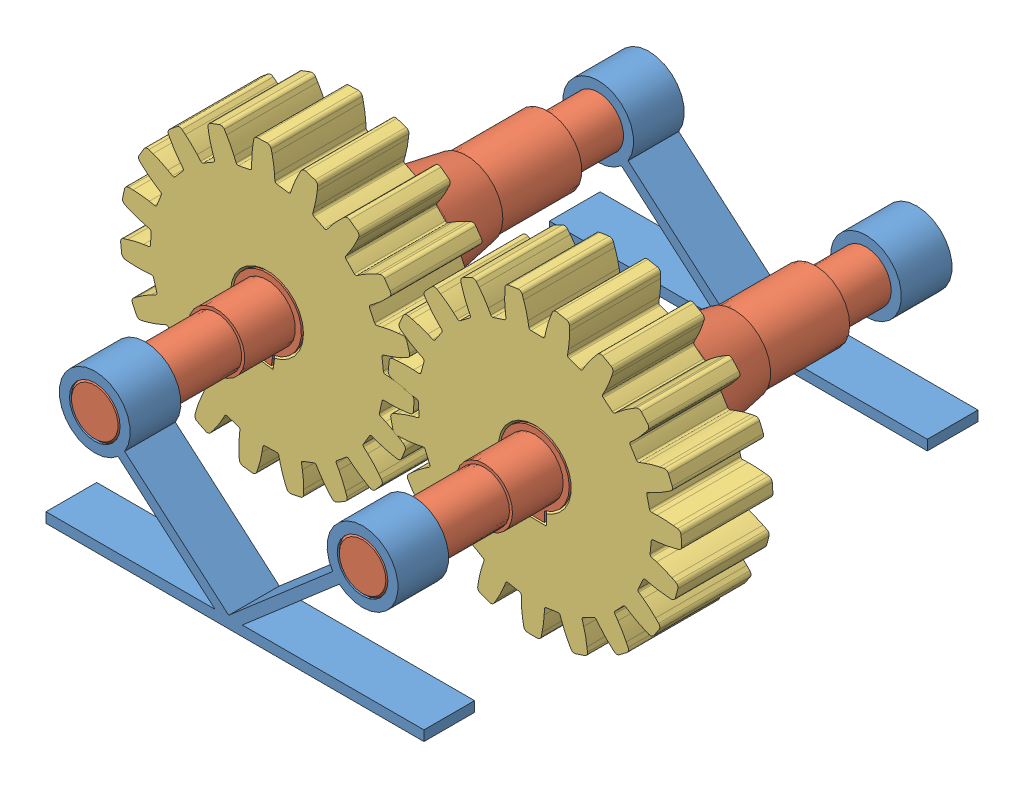
SolidWorks assembly Gear-Box-Assembly, configuration Default. Lengths in mm.
Overall size (287.15 162.37 273.36).
6 component instances, 3 part files, 16 mates.
Components (placement in the parent):
- Base-1: Base [Default] at (37.7602 101.1574 169.9785) size (186.47 77.1 25)
- Shaft-1: Shaft [Default] at (103.8202 101.1574 45.8002) x (0 0 1) z (0.999858 -0.016835 0) size (273.36 46 46)
- Shaft-2: Shaft [Default] at (-28.2998 101.1574 45.8002) x (0 0 1) z (0.991113 -0.133025 0) size (273.36 46 46)
- Spur-Gear-1: Spur-Gear [Default] at (103.8202 101.1574 74.9785) x (-0.999858 0.016835 0) z (0 0 1) size (144.83 144.39 45)
- Spur-Gear-2: Spur-Gear [Default] at (-28.2998 101.1574 74.9785) x (-0.991113 0.133025 0) z (0 0 1) size (144.83 144.39 45)
- Base-2: Base [Default] at (37.7602 101.1574 -78.378) size (186.47 77.1 25)
Mates (geometry in assembly coordinates):
- Concentric4: concentric anti-aligned: cylinder of Base-1 through (103.8202 101.1574 182.4785) axis (0 0 -1) radius 12.5; cylinder of Shaft-1 through (103.8202 101.1574 182.4785) axis (0 0 1) radius 12.5
- Concentric5: concentric anti-aligned: cylinder of Base-1 through (-28.2998 101.1574 182.4785) axis (0 0 -1) radius 12.5; cylinder of Shaft-2 through (-28.2998 101.1574 182.4785) axis (0 0 1) radius 12.5
- Concentric9: concentric anti-aligned: cylinder of Shaft-1 through (103.8202 101.1574 182.4785) axis (0 0 1) radius 12.5; cylinder of Base-1 through (103.8202 101.1574 182.4785) axis (0 0 -1) radius 12.5
- Concentric11: concentric anti-aligned: cylinder of Base-1 through (-28.2998 101.1574 182.4785) axis (0 0 -1) radius 12.5; cylinder of Shaft-2 through (-28.2998 101.1574 182.4785) axis (0 0 1) radius 12.5
- Concentric12: concentric anti-aligned: cylinder of Base-1 through (103.8202 101.1574 182.4785) axis (0 0 -1) radius 12.5; cylinder of Shaft-1 through (103.8202 101.1574 182.4785) axis (0 0 1) radius 12.5
- Coincident3: coincident aligned: plane of Base-1 through (-28.2998 101.1574 182.4785) normal (0 0 1); plane of Shaft-1 through (103.6098 88.6592 182.4785) normal (0 0 1)
- Coincident4: coincident aligned: plane of Base-1 through (-28.2998 101.1574 182.4785) normal (0 0 1); plane of Shaft-2 through (-29.9626 88.7685 182.4785) normal (0 0 1)
- Concentric13: concentric anti-aligned: cylinder of Shaft-1 through (103.8202 101.1574 182.4785) axis (0 0 1) radius 17; cylinder of Spur-Gear-1 through (103.8202 101.1574 97.4785) axis (0 0 -1) radius 17
- Coincident5: coincident aligned: plane of Shaft-1 through (103.534 84.1598 97.4785) normal (0 0 1); plane of Spur-Gear-1 through (103.8202 101.1574 97.4785) normal (0 0 1)
- Concentric14: concentric anti-aligned: cylinder of Shaft-2 through (-28.2998 101.1574 182.4785) axis (0 0 1) radius 17; cylinder of Spur-Gear-2 through (-28.2998 101.1574 97.4785) axis (0 0 -1) radius 17
- Coincident6: coincident aligned: plane of Shaft-2 through (-30.5612 84.3085 97.4785) normal (0 0 1); plane of Spur-Gear-2 through (-28.2998 101.1574 97.4785) normal (0 0 1)
- Coincident7: coincident anti-aligned: plane of Shaft-1 through (98.4632 79.9965 41.2981) normal (-0.999858 0.016835 0); plane of Spur-Gear-1 through (98.8209 101.2416 97.4785) normal (0.999858 -0.016835 0)
- Coincident8: coincident anti-aligned: plane of Shaft-2 through (-26.1708 79.433 41.2981) normal (0.991113 -0.133025 0); plane of Spur-Gear-2 through (-23.3442 100.4923 97.4785) normal (-0.991113 0.133025 0)
- GearMate1: gear = 115 : 115 mm: circle of Spur-Gear-2; circle of Spur-Gear-1
- Concentric15: concentric anti-aligned: cylinder of Shaft-1 through (103.8202 101.1574 182.4785) axis (0 0 1) radius 12.5; cylinder of Base-2 through (103.8202 101.1574 -65.878) axis (0 0 -1) radius 12.5
- Coincident9: coincident aligned: plane of Shaft-1 through (103.8202 101.1574 -90.878) normal (0 0 -1); plane of Base-2 through (-28.2998 101.1574 -90.878) normal (0 0 -1)
